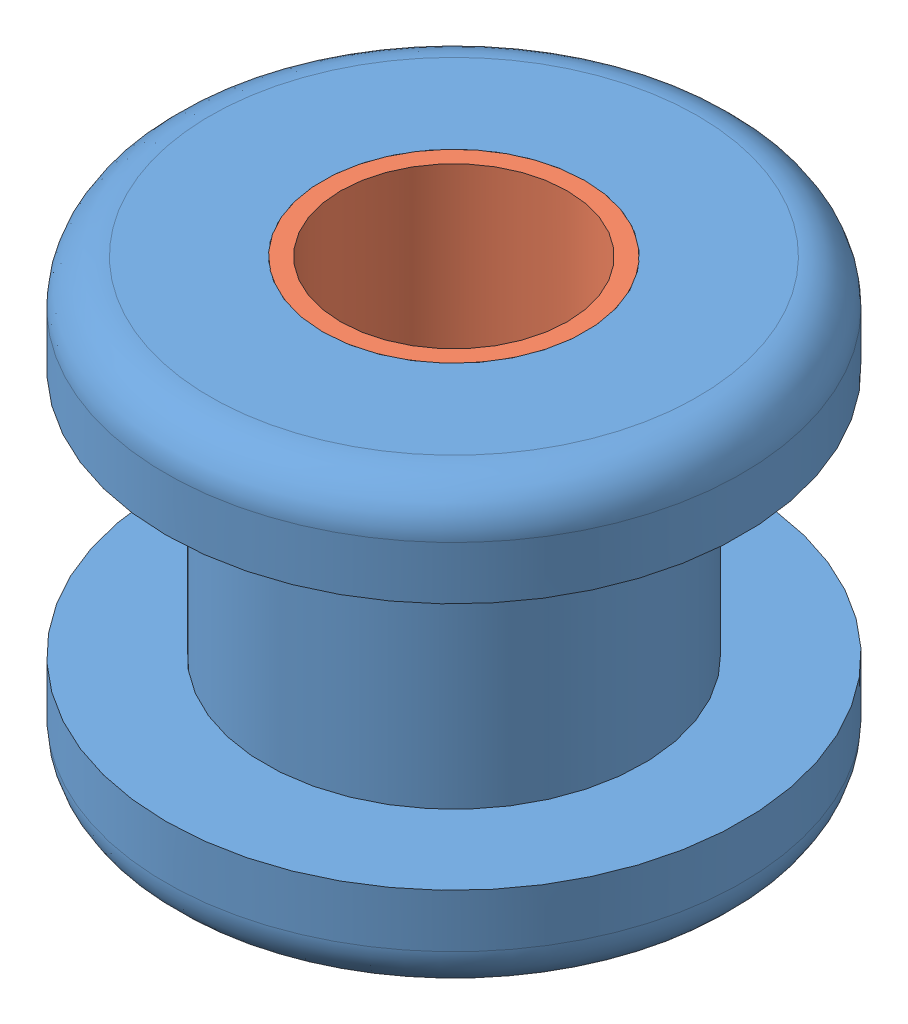
SolidWorks assembly FS5109M_Ensemble silent-bloc, configuration Défaut. Lengths in mm.
Overall size (6.5 5.2 6.5).
2 component instances, 2 part files, 4 mates.
Components (placement in the parent):
- FS5109M_silent-bloc-1: FS5109M_silent-bloc [Défaut] at origin size (6.5 5 6.5)
- FS5109M_silent-bloc_douille-1: FS5109M_silent-bloc_douille [Défaut] at (0 -2.7 0) x (-1 0 0) z (0 0 1) size (4.5 5.2 4.5)
Mates (geometry in assembly coordinates):
- Coïncidente1: coordinate: point of FS5109M_silent-bloc-1; point of assembly
- Coïncidente2: coincident: plane of FS5109M_silent-bloc-1 through (0 0 0) normal (0 0 1); plane of FS5109M_silent-bloc_douille-1 through (0 5.3816 0) normal (0 0 1)
- Coïncidente3: coincident: plane of FS5109M_silent-bloc-1 through (0 0 0) normal (1 0 0); plane of FS5109M_silent-bloc_douille-1
- Coïncidente4: coincident aligned: plane of FS5109M_silent-bloc-1 through (-2.75 2.5 0) normal (0 1 0); plane of FS5109M_silent-bloc_douille-1 through (1.28 2.5 0) normal (0 1 0)
